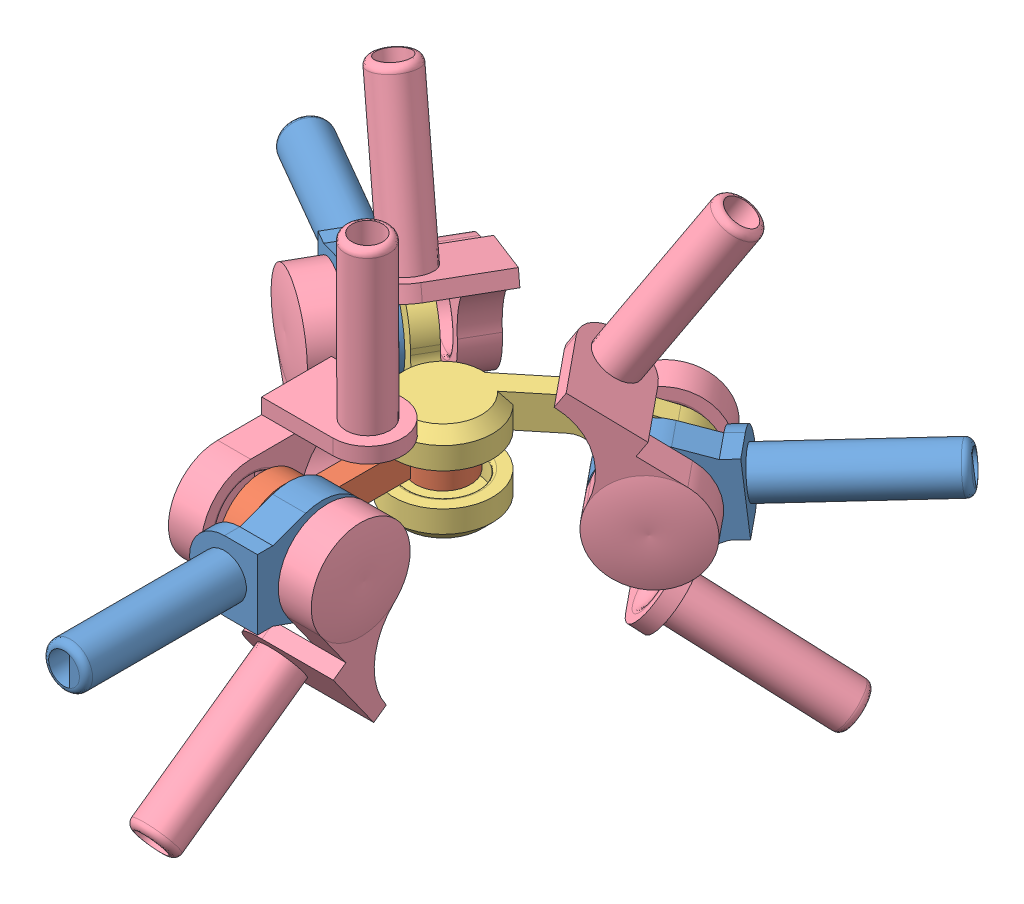
SolidWorks assembly Class9_joint, configuration 默认. Lengths in mm.
Overall size (60.49 44.67 60.95).
12 component instances, 4 part files, 34 mates.
Components (placement in the parent):
- joint_bearing_central-1: joint_bearing_central [默认] at (7.3851 -2.1507 34.1852) x (0 -1 0) z (1 0 0) size (9 25 6.17)
- mid_ear-1: mid_ear [默认] at (7.3851 -3.6507 -0.3148) size (5 8 20.5)
- side_ear-1: side_ear [默认] at (7.3851 -0.6507 -0.3148) x (0.633086 0 0.774081) z (0.774081 0 -0.633086) size (9 9.5 22.5)
- side_ear-2: side_ear [默认] at (7.3851 -3.6507 -0.3148) x (-0.5 0 0.866025) z (-0.866025 0 -0.5) size (9 9.5 22.5)
- joint_bearing_central-2: joint_bearing_central [默认] at (34.0113 -1.1007 -22.0913) x (-0.077409 0.994987 0.063309) z (0.633086 0 0.774081) size (9 25 6.17)
- joint_bearing_central-3: joint_bearing_central [默认] at (-22.4928 -1.1507 -17.5648) x (0 -1 0) z (-0.5 0 0.866025) size (9 25 6.17)
- joint_bearing_c9-1: joint_bearing_c9 [默认] at (-3.345 20.5105 -6.5098) x (0.836314 0.25969 0.482846) z (0.5 0 -0.866025) size (14.86 25 10.02)
- joint_bearing_c9-2: joint_bearing_c9 [默认] at (22.3293 17.9123 -12.537) x (-0.645935 0.551078 0.528281) z (0.633086 0 0.774081) size (14.86 25 10.02)
- joint_bearing_c9-3: joint_bearing_c9 [默认] at (7.3851 -19.8811 26.2326) x (0 -0.815015 -0.57944) z (1 0 0) size (14.86 25 10.02)
- joint_bearing_c9-4: joint_bearing_c9 [默认] at (7.3851 18.3741 6.5766) x (0 0.003481 -0.999994) z (-1 0 0) size (14.86 25 10.02)
- joint_bearing_c9-5: joint_bearing_c9 [默认] at (28.1013 -20.727 -17.2577) x (-0.44082 -0.822009 0.360527) z (-0.633086 0 -0.774081) size (14.86 25 10.02)
- joint_bearing_c9-6: joint_bearing_c9 [默认] at (-14.2739 -19.8748 -12.8196) x (0.559472 -0.763319 0.323011) z (-0.5 0 0.866025) size (14.86 25 10.02)
Mates (geometry in assembly coordinates):
- 同心1: concentric aligned: cylinder of mid_ear-1 through (7.3851 -0.6507 -0.3148) axis (0 -1 0) radius 1.65; cylinder of side_ear-1 through (7.3851 1.3493 -0.3148) axis (0 -1 0) radius 3.15
- 重合2: coincident anti-aligned: plane of mid_ear-1 through (7.3851 -0.6507 -0.3148) normal (0 1 0); plane of side_ear-1 through (7.3851 -0.6507 -0.3148) normal (0 -1 0)
- 同心2: concentric anti-aligned: cylinder of mid_ear-1 through (7.3851 -0.6507 -0.3148) axis (0 -1 0) radius 1.65; cylinder of side_ear-2 through (7.3851 -5.6507 -0.3148) axis (0 1 0) radius 3.15
- 重合3: coincident anti-aligned: plane of mid_ear-1 through (7.3851 -3.6507 -0.3148) normal (0 -1 0); plane of side_ear-2 through (7.3851 -3.6507 -0.3148) normal (0 1 0)
- 同心3: concentric anti-aligned: cylinder of joint_bearing_central-1 through (9.8851 -2.1507 13.6852) axis (-1 0 0) radius 3.15; cylinder of mid_ear-1 through (4.8841 -2.1507 13.6852) axis (1 0 0) radius 1.65
- 距离4: distance = 0.5 mm anti-aligned: plane of joint_bearing_central-1 through (7.3851 -2.1507 13.6852) normal (-1 0 0); plane of mid_ear-1 through (6.8851 -0.8507 -2.8168) normal (1 0 0)
- 同心4: concentric anti-aligned: cylinder of side_ear-2 through (-3.4893 -1.1507 -9.4799) axis (-0.5 0 0.866025) radius 1.65; cylinder of joint_bearing_central-3 through (-5.9893 -1.1507 -5.1498) axis (0.5 0 -0.866025) radius 3.15
- 距离3: distance = 0.5 mm anti-aligned: plane of side_ear-2 through (7.6351 -3.6507 -0.7479) normal (-0.5 0 0.866025); plane of joint_bearing_central-3 through (-4.7393 -1.1507 -7.3148) normal (0.5 0 -0.866025)
- 同心5: concentric anti-aligned: cylinder of side_ear-1 through (16.6395 -3.1507 -11.1133) axis (0.633086 0 0.774081) radius 1.65; cylinder of joint_bearing_central-2 through (19.8049 -3.1507 -7.2428) axis (-0.633086 0 -0.774081) radius 3.15
- 同心6: concentric anti-aligned: cylinder of side_ear-1 through (16.6395 -3.1507 -11.1133) axis (0.633086 0 0.774081) radius 1.65; cylinder of joint_bearing_central-2 through (19.8049 -3.1507 -7.2428) axis (-0.633086 0 -0.774081) radius 3.15
- 距离2: distance = 0.5 mm anti-aligned: plane of side_ear-1 through (7.0685 -0.6507 -0.7019) normal (0.633086 0 0.774081); plane of joint_bearing_central-2 through (18.2222 -3.1507 -9.1781) normal (-0.633086 0 -0.774081)
- 同心7: concentric aligned: cylinder of side_ear-2 through (-3.4893 -1.1507 -9.4799) axis (-0.5 0 0.866025) radius 1.65; cylinder of joint_bearing_c9-1 through (-1.6018 -1.1507 -12.7492) axis (-0.5 0 0.866025) radius 3.15
- 距离5: distance = 1 mm anti-aligned: plane of side_ear-2 through (-3.4893 -1.1507 -9.4799) normal (0.5 0 -0.866025); plane of joint_bearing_c9-1 through (-2.9893 -1.1507 -10.3459) normal (-0.5 0 0.866025)
- 同心8: concentric aligned: cylinder of joint_bearing_central-3 through (-6.3273 -1.1507 -4.5643) axis (0.5 0 -0.866025) radius 1.8; cylinder of joint_bearing_c9-6 through (-7.8768 -1.1507 -1.8805) axis (0.5 0 -0.866025) radius 3.15
- 距离6: distance = 0.5 mm anti-aligned: plane of joint_bearing_c9-6 through (-6.4893 -1.1507 -4.2838) normal (0.5 0 -0.866025); plane of joint_bearing_central-3 through (-6.2393 -1.1507 -4.7168) normal (-0.5 0 0.866025)
- 同心9: concentric aligned: cylinder of side_ear-1 through (16.6395 -3.1507 -11.1133) axis (0.633086 0 0.774081) radius 1.65; cylinder of joint_bearing_c9-5 through (14.2496 -3.1507 -14.0354) axis (0.633086 0 0.774081) radius 3.15
- 距离7: distance = 1 mm anti-aligned: plane of side_ear-1 through (16.6395 -3.1507 -11.1133) normal (-0.633086 0 -0.774081); plane of joint_bearing_c9-5 through (16.0064 -3.1507 -11.8873) normal (0.633086 0 0.774081)
- 同心10: concentric aligned: cylinder of joint_bearing_central-2 through (20.2329 -3.1507 -6.7196) axis (-0.633086 0 -0.774081) radius 1.8; cylinder of joint_bearing_c9-2 through (22.1948 -3.1507 -4.3207) axis (-0.633086 0 -0.774081) radius 3.15
- 距离9: distance = 0.5 mm anti-aligned: plane of joint_bearing_c9-2 through (20.438 -3.1507 -6.4688) normal (-0.633086 0 -0.774081); plane of joint_bearing_central-2 through (20.1215 -3.1507 -6.8558) normal (0.633086 0 0.774081)
- 同心11: concentric aligned: cylinder of mid_ear-1 through (4.8841 -2.1507 13.6852) axis (1 0 0) radius 1.65; cylinder of joint_bearing_c9-4 through (1.1101 -2.1507 13.6852) axis (1 0 0) radius 3.15
- 距离10: distance = 1 mm anti-aligned: plane of mid_ear-1 through (4.8851 -0.8507 -2.8168) normal (-1 0 0); plane of joint_bearing_c9-4 through (3.8851 -2.1507 13.6852) normal (1 0 0)
- 同心12: concentric aligned: cylinder of joint_bearing_central-1 through (10.5611 -2.1507 13.6852) axis (-1 0 0) radius 1.8; cylinder of joint_bearing_c9-3 through (13.6601 -2.1507 13.6852) axis (-1 0 0) radius 3.15
- 距离11: distance = 0.5 mm anti-aligned: plane of joint_bearing_c9-3 through (10.8851 -2.1507 13.6852) normal (-1 0 0); plane of joint_bearing_central-1 through (10.3851 -2.1507 13.6852) normal (1 0 0)
- 角度1: planar angle = 2.094395 rad anti-aligned: plane of joint_bearing_central-1 through (10.3851 -2.1507 13.6852) normal (1 0 0); plane of joint_bearing_central-2 through (16.251 -3.1507 -3.6904) normal (0.633086 0 0.774081)
- 角度2: planar angle = 2.094395 rad aligned: plane of joint_bearing_central-3 through (-0.4092 -1.1507 -4.8148) normal (0.5 0 -0.866025); plane of mid_ear-1 through (4.8851 -0.8507 -2.8168) normal (-1 0 0)
- 平行3: parallel aligned: plane of side_ear-1 through (7.3851 4.3493 -0.3148) normal (0 1 0); plane of joint_bearing_central-3 through (0.4681 2.0243 -15.3342) normal (0 1 0)
- 平行4: parallel aligned: plane of side_ear-1 through (7.3851 4.3493 -0.3148) normal (0 1 0); unknown of joint_bearing_central-2
- 平行5: parallel aligned: plane of joint_bearing_central-1 through (-2.1636 2.0243 13.1852) normal (0 1 0); plane of side_ear-1 through (7.3851 4.3493 -0.3148) normal (0 1 0)
- 相切1: tangent anti-aligned: cylinder of side_ear-1 through (7.3851 4.3493 -0.3148) axis (0 -1 0) radius 4.5; unknown of joint_bearing_c9-4
- 相切2: tangent anti-aligned: cylinder of side_ear-1 through (7.3851 4.3493 -0.3148) axis (0 -1 0) radius 4.5; unknown of joint_bearing_c9-1
- 相切3: tangent anti-aligned: cylinder of side_ear-1 through (7.3851 4.3493 -0.3148) axis (0 -1 0) radius 4.5; unknown of joint_bearing_c9-2
- 相切7: tangent anti-aligned: cylinder of side_ear-2 through (7.3851 -6.6507 -0.3148) axis (0 1 0) radius 4.5; unknown of joint_bearing_c9-6
- 相切8: tangent anti-aligned: cylinder of side_ear-2 through (7.3851 -6.6507 -0.3148) axis (0 1 0) radius 4.5; unknown of joint_bearing_c9-3
- 相切9: tangent anti-aligned: cylinder of side_ear-2 through (7.3851 -6.6507 -0.3148) axis (0 1 0) radius 4.5; unknown of joint_bearing_c9-5
